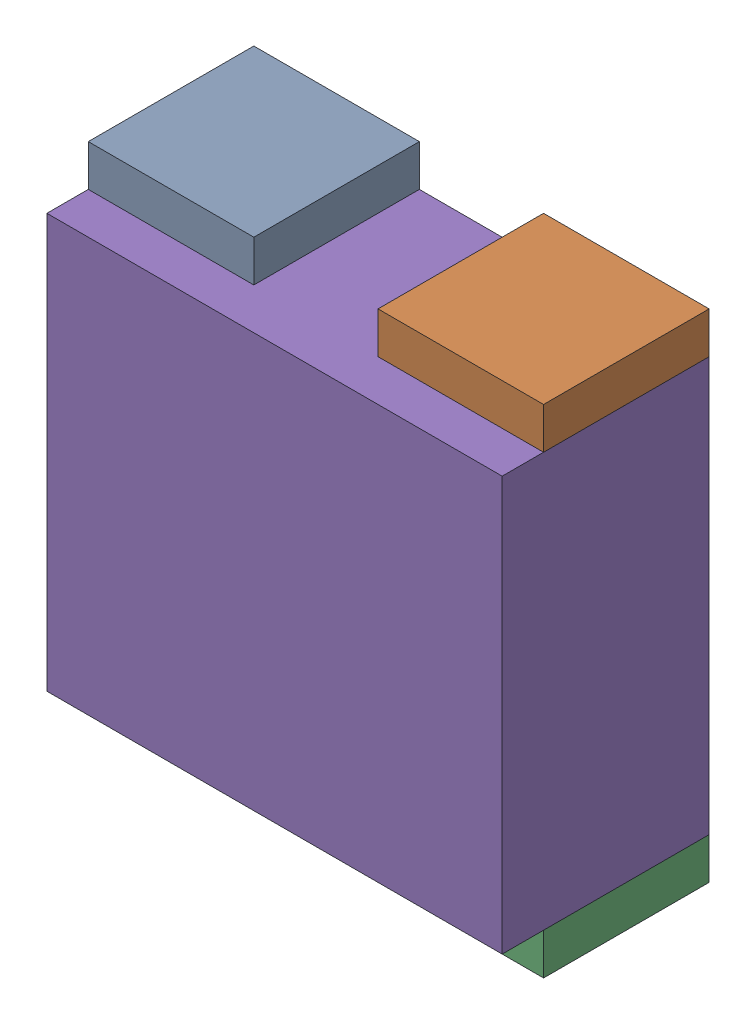
SolidWorks assembly RN24, configuration Default. Lengths in mm.
Overall size (1.1 1.2 0.5).
10 component instances, 2 part files, 0 mates.
Components (placement in the parent):
- 810157616-1: 810157616 [Default] at (124.95 79.3 0) size (0.4 0.1 0.4)
  - Extruded_12-1: Extruded_12 [Default] at origin size (0.4 0.1 0.4)
- 810157616-2: 810157616 [Default] at (125.65 79.3 0) size (0.4 0.1 0.4)
  - Extruded_12-1: Extruded_12 [Default] at origin size (0.4 0.1 0.4)
- 810157616-3: 810157616 [Default] at (125.65 78.2 0) size (0.4 0.1 0.4)
  - Extruded_12-1: Extruded_12 [Default] at origin size (0.4 0.1 0.4)
- 810157616-4: 810157616 [Default] at (124.95 78.2 0) size (0.4 0.1 0.4)
  - Extruded_12-1: Extruded_12 [Default] at origin size (0.4 0.1 0.4)
- 810156720-1: 810156720 [Default] at (125.3 78.75 0) size (1.1 1 0.5)
  - Extruded_13-1: Extruded_13 [Default] at origin size (1.1 1 0.5)
